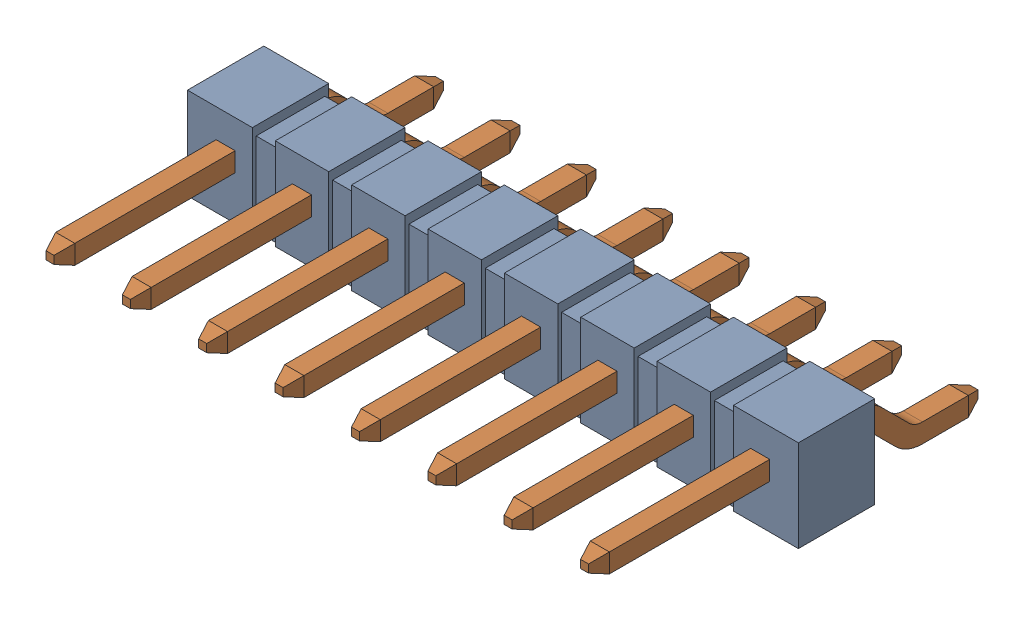
SolidWorks assembly TSM_108_01_T_SH, configuration Default. Lengths in mm.
Overall size (20.32 3.05 12.95).
2 component instances, 2 part files, 0 mates.
Components (placement in the parent):
- _TSM_108_01_SH_body_2-1: _TSM_108_01_SH_body_2 [Default] at (0 1.524 0) size (20.32 3.05 2.54)
- _T_1S6_08__01_8_SH__4-1: _T_1S6_08__01_8_SH__4 [Default] at (0 0 -5.842) x (1 0 0) z (0 -1 0) size (18.42 12.95 2.1)
